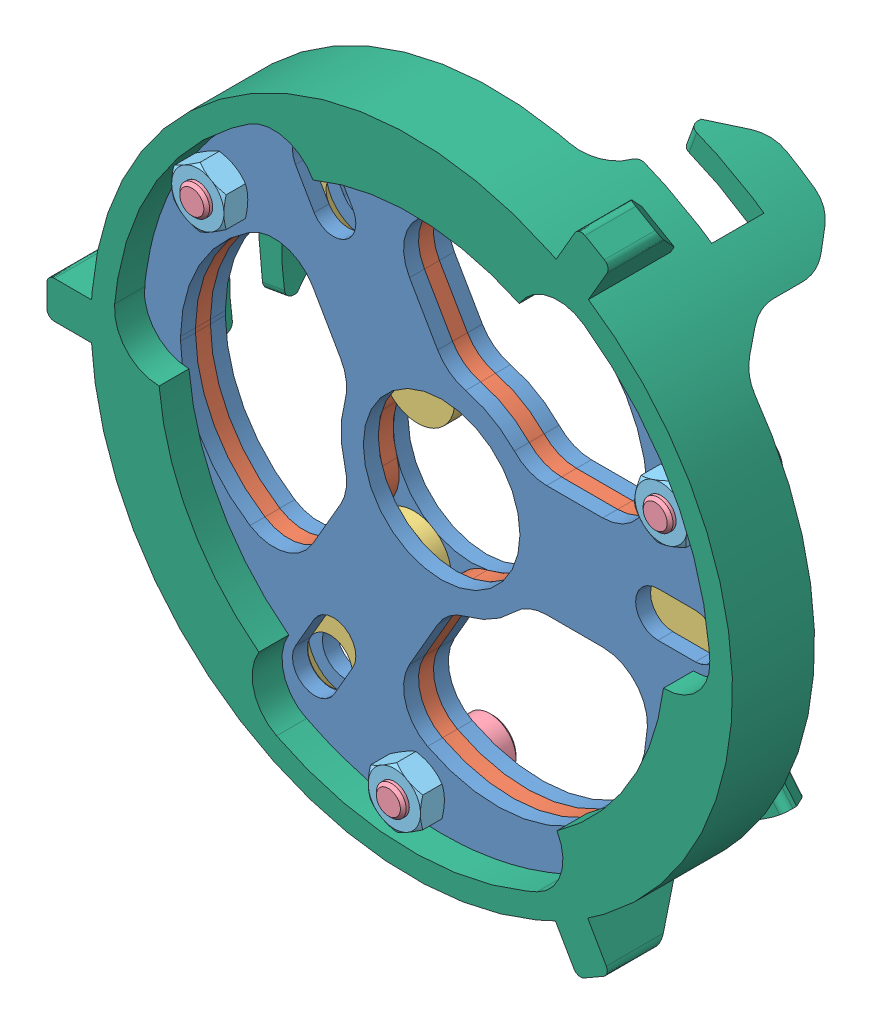
SolidWorks assembly Tri-Claw-Gripper-Tool, configuration Default. Lengths in mm.
Overall size (123.84 122.12 170.54).
14 component instances, 7 part files, 35 mates.
Components (placement in the parent):
- ClawToolFrame-1: ClawToolFrame [Default] at origin size (80 80 2)
- ClawToolGuide-1: ClawToolGuide [Default] at (0 0 2) size (80 80 2)
- ClawToolFinger-1: ClawToolFinger [Default] at (2.7861 0 2) size (28.5 10 2)
- ClawToolFinger-2: ClawToolFinger [Default] at (2.5101 -4.3477 2) x (-0.5 0.866025 0) z (0 0 1) size (28.5 10 2)
- ClawToolFinger-3: ClawToolFinger [Default] at (0.0487 0.0844 2) x (-0.5 -0.866025 0) z (0 0 1) size (28.5 10 2)
- socket head cap screw_am-1: socket head cap screw_am [B18.3.1M - 4 x 0.7 x 10 Hex SHCS -- 10NHX] at (32.6271 15.2143 -4) x (0 0 1) z (-1 0 0) size (14 7 7)
- socket head cap screw_am-2: socket head cap screw_am [B18.3.1M - 4 x 0.7 x 10 Hex SHCS -- 10NHX] at (-29.4895 20.6488 -4) x (0 0 1) z (-1 0 0) size (14 7 7)
- socket head cap screw_am-3: socket head cap screw_am [B18.3.1M - 4 x 0.7 x 10 Hex SHCS -- 10NHX] at (-3.1376 -35.863 -4) x (0 0 1) z (-1 0 0) size (14 7 7)
- hex nut style 1_am-2: hex nut style 1_am [B18.2.4.1M - Hex nut, Style 1,  M4 x 0.7 --D-N] at (-3.1376 -35.863 9.2) size (7 8.08 3.2)
- hex nut style 1_am-3: hex nut style 1_am [B18.2.4.1M - Hex nut, Style 1,  M4 x 0.7 --D-N] at (-29.4895 20.6488 9.2) size (7 8.08 3.2)
- hex nut style 1_am-4: hex nut style 1_am [B18.2.4.1M - Hex nut, Style 1,  M4 x 0.7 --D-N] at (32.6271 15.2143 9.2) x (0.979518 -0.201355 0) z (0 0 1) size (7 8.08 3.2)
- ClawToolSecuring Cap-1: ClawToolSecuring Cap [Default] at (0 0 10) x (-0.498847 0.86669 0) z (0 0 1) size (91.93 86.51 29.29)
- ClawToolFrame-2: ClawToolFrame [Default] at (0 0 4) size (80 80 2)
- ClawToolBaseMount-1: ClawToolBaseMount [Default] at (0 0 10) x (0.999999 -0.001331 0) z (0 0 1) size (135 110 21.28) (hidden)
Mates (geometry in assembly coordinates):
- Coincident5: coordinate: point of ClawToolFrame-1; point of assembly
- Coincident7: coordinate: point of ClawToolFrame-1; point of assembly
- Concentric5: concentric: cylinder of ClawToolFrame-1 through (0 0 2) axis (0 0 -1) radius 40; cylinder of ClawToolGuide-1 through (0 0 4) axis (0 0 -1) radius 40
- Coincident8: coincident: plane of ClawToolFrame-1 through (0 0 2) normal (0 0 1); plane of ClawToolGuide-1 through (0 0 2) normal (0 0 -1)
- Concentric6: concentric: cylinder of ClawToolFrame-1 through (-29.4895 20.6488 -8) axis (0 0 1) radius 2; cylinder of ClawToolGuide-1 through (-29.4895 20.6488 -6) axis (0 0 1) radius 2
- Coincident9: coincident: plane of ClawToolFrame-1 through (0 0 2) normal (0 0 1); plane of ClawToolFinger-1 through (36.7861 0 2) normal (0 0 -1)
- Coincident10: coincident: plane of ClawToolGuide-1 through (0 5 1) normal (0 -1 0); plane of ClawToolFinger-1 through (18.2861 5 4) normal (0 1 0)
- Coincident11: coincident: plane of ClawToolFrame-1 through (0 0 2) normal (0 0 1); plane of ClawToolFinger-3 through (-16.9513 -29.3605 2) normal (0 0 -1)
- Coincident12: coincident: plane of ClawToolGuide-1 through (-21.3301 -26.9449 1) normal (0.866025 -0.5 0); plane of ClawToolFinger-3 through (-21.2814 -26.8605 4) normal (-0.866025 0.5 0)
- Coincident13: coincident: plane of ClawToolFrame-1 through (0 0 2) normal (0 0 1); plane of ClawToolFinger-2 through (-14.4899 25.0972 2) normal (0 0 -1)
- Coincident14: coincident: plane of ClawToolGuide-1 through (-4.3301 -2.5 1) normal (0.866025 0.5 0); plane of ClawToolFinger-2 through (-9.57 6.5757 4) normal (-0.866025 -0.5 0)
- Coincident15: coincident: plane of ClawToolGuide-1 through (0 0 4) normal (0 0 1); plane of ClawToolFrame-2 through (0 0 4) normal (0 0 -1)
- Concentric8: concentric: cylinder of ClawToolGuide-1 through (-29.4895 20.6488 -6) axis (0 0 1) radius 2; cylinder of ClawToolFrame-2 through (-29.4895 20.6488 -4) axis (0 0 1) radius 2
- Concentric9: concentric: cylinder of ClawToolGuide-1 through (0 0 4) axis (0 0 -1) radius 40; cylinder of ClawToolFrame-2 through (0 0 6) axis (0 0 -1) radius 40
- Concentric10: concentric: cylinder of ClawToolFrame-1 through (32.6271 15.2143 -8) axis (0 0 1) radius 2; cylinder of socket head cap screw_am-1 through (32.6271 15.2143 -35.75) axis (0 0 -1) radius 3.5
- Coincident16: coincident: plane of ClawToolFrame-1 through (0 0 0) normal (0 0 -1); plane of socket head cap screw_am-1 through (32.6271 18.7143 0) normal (0 0 1)
- Concentric11: concentric: cylinder of ClawToolFrame-1 through (-29.4895 20.6488 -8) axis (0 0 1) radius 2; cylinder of socket head cap screw_am-2 through (-29.4895 20.6488 -35.75) axis (0 0 -1) radius 3.5
- Coincident17: coincident: plane of ClawToolFrame-1 through (0 0 0) normal (0 0 -1); plane of socket head cap screw_am-2 through (-29.4895 24.1488 0) normal (0 0 1)
- Concentric12: concentric: cylinder of ClawToolFrame-1 through (-3.1376 -35.863 -8) axis (0 0 1) radius 2; cylinder of socket head cap screw_am-3 through (-3.1376 -35.863 -35.75) axis (0 0 -1) radius 3.5
- Coincident18: coincident: plane of ClawToolFrame-1 through (0 0 0) normal (0 0 -1); plane of socket head cap screw_am-3 through (-3.1376 -32.363 0) normal (0 0 1)
- Concentric13: concentric: cylinder of ClawToolFrame-2 through (-3.1376 -35.863 -4) axis (0 0 1) radius 2; cylinder of hex nut style 1_am-2 through (-3.1376 -35.863 -15.8375) axis (0 0 1) radius 2
- Coincident19: coincident: plane of ClawToolFrame-2 through (0 0 6) normal (0 0 1); plane of hex nut style 1_am-2 through (-3.1376 -31.8216 6) normal (0 0 -1)
- Concentric14: concentric: cylinder of ClawToolFrame-2 through (-29.4895 20.6488 -4) axis (0 0 1) radius 2; cylinder of hex nut style 1_am-3 through (-29.4895 20.6488 -15.8375) axis (0 0 1) radius 2
- Coincident20: coincident: plane of ClawToolFrame-2 through (0 0 6) normal (0 0 1); plane of hex nut style 1_am-3 through (-29.4895 24.6902 6) normal (0 0 -1)
- Concentric15: concentric: cylinder of ClawToolFrame-2 through (32.6271 15.2143 -4) axis (0 0 1) radius 2; cylinder of hex nut style 1_am-4 through (32.6271 15.2143 -15.8375) axis (0 0 1) radius 2
- Coincident22: coincident: plane of ClawToolFrame-2 through (0 0 6) normal (0 0 1); plane of ClawToolSecuring Cap-1 through (0 0 6) normal (0 0 -1)
- Concentric16: concentric: cylinder of ClawToolFrame-2 through (0 0 6) axis (0 0 -1) radius 40; cylinder of ClawToolSecuring Cap-1 through (0 0 6) axis (0 0 1) radius 43
- Coincident23: coincident: plane of ClawToolGuide-1 through (0 0 4) normal (0 0 1); plane of ClawToolFrame-2 through (0 0 4) normal (0 0 -1)
- Concentric17: concentric: circle of ClawToolFrame-1; cylinder of ClawToolFrame-2 through (0 0 6) axis (0 0 -1) radius 40
- Coincident24: coincident: plane of ClawToolFrame-1 through (2.5981 1.5 2) normal (-0.866025 -0.5 0); plane of ClawToolFrame-2 through (2.5981 1.5 6) normal (-0.866025 -0.5 0)
- Concentric18: concentric: cylinder of ClawToolSecuring Cap-1 through (0 0 -1) axis (0 0 1) radius 40; cylinder of ClawToolFrame-2 through (0 0 6) axis (0 0 -1) radius 40
- Coincident25: coincident: plane of ClawToolSecuring Cap-1 through (0 0 6) normal (0 0 -1); plane of ClawToolFrame-2 through (0 0 6) normal (0 0 1)
- Concentric19: concentric: cylinder of ClawToolSecuring Cap-1 through (0 0 6) axis (0 0 1) radius 43; cylinder of ClawToolBaseMount-1 through (0 0 0) axis (0 0 1) radius 43.5
- Coincident26: coincident: plane of ClawToolSecuring Cap-1 through (0 0 10) normal (0 0 1); plane of ClawToolBaseMount-1 through (0 0 10) normal (0 0 -1)
- Parallel1: parallel: plane of ClawToolSecuring Cap-1 through (-48.9239 2.5651 -1) normal (-0.999999 0.001331 0); line of ClawToolBaseMount-1 through (-50.0039 -2.9335 10) axis (0.001331 0.999999 0)
